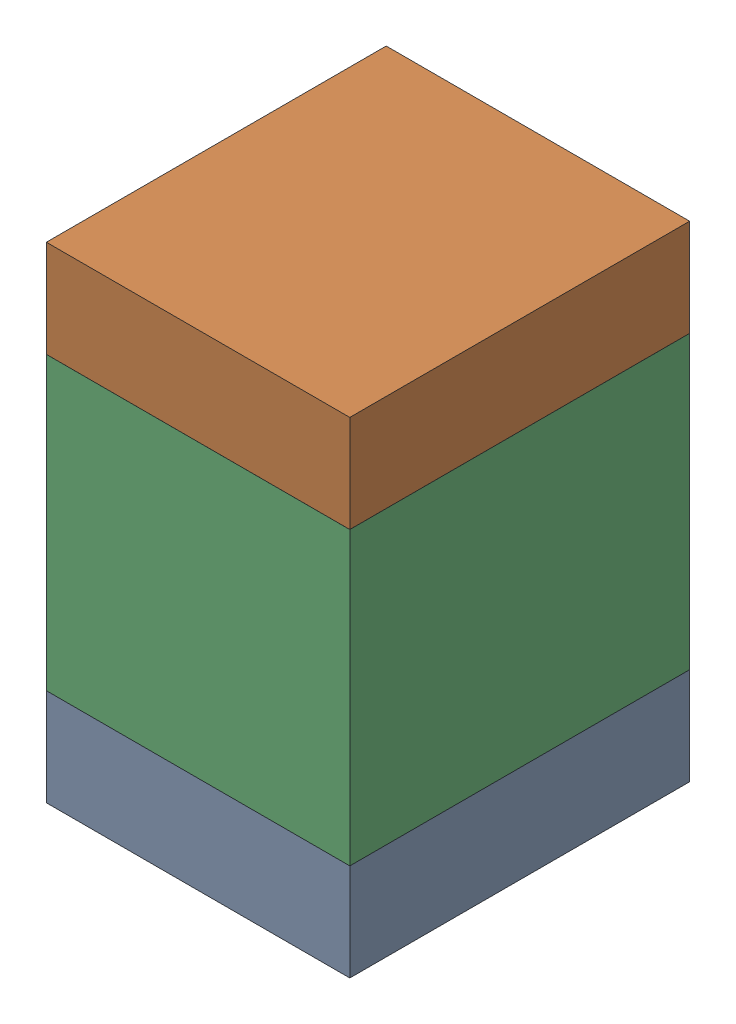
SolidWorks assembly C28, configuration ﾃﾞﾌｫﾙﾄ. Lengths in mm.
Overall size (1.25 2 1.4).
6 component instances, 2 part files, 0 mates.
Components (placement in the parent):
- 689259336-1: 689259336 [ﾃﾞﾌｫﾙﾄ] at (70 21.2001 0) size (1.25 0.4 1.4)
  - Extruded_8-1: Extruded_8 [ﾃﾞﾌｫﾙﾄ] at origin size (1.25 0.4 1.4)
- 689259336-2: 689259336 [ﾃﾞﾌｫﾙﾄ] at (70 22.8001 0) size (1.25 0.4 1.4)
  - Extruded_8-1: Extruded_8 [ﾃﾞﾌｫﾙﾄ] at origin size (1.25 0.4 1.4)
- 689259472-1: 689259472 [ﾃﾞﾌｫﾙﾄ] at (70 22 0) size (1.25 1.2 1.4)
  - Extruded_9-1: Extruded_9 [ﾃﾞﾌｫﾙﾄ] at origin size (1.25 1.2 1.4)
